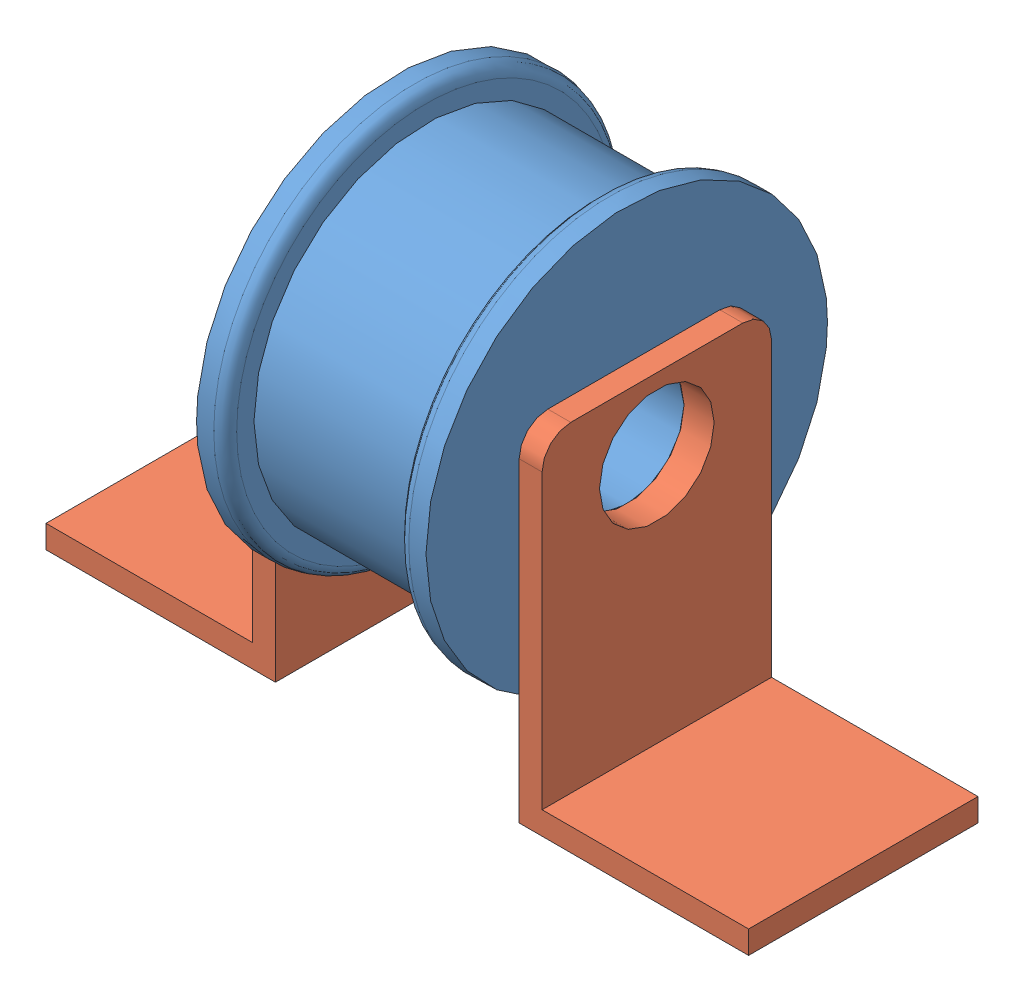
SolidWorks assembly Idler_Assem, configuration Default. Lengths in mm.
Overall size (77.79 46.04 31.75).
3 component instances, 2 part files, 6 mates.
Components (placement in the parent):
- Idler-1: Idler [Default] at origin size (25.4 31.75 31.75)
- Idler_Support-1: Idler_Support [Default] at (23.0188 -30.1625 -12.7) x (0 0 1) z (-1 0 0) size (25.4 38.1 26.19)
- Idler_Support-2: Idler_Support [Default] at (-3.9688 -30.1625 12.7) x (0 0 -1) z (1 0 0) size (25.4 38.1 26.19)
Mates (geometry in assembly coordinates):
- Concentric2: concentric anti-aligned: circle of Idler-1; circle of Idler_Support-1
- Coincident1: coincident anti-aligned: plane of Idler-1 through (22.225 0 0) normal (1 0 0); plane of Idler_Support-1 through (22.225 0 0) normal (-1 0 0)
- Coincident2: coincident anti-aligned: plane of Idler-1 through (-3.175 0 0) normal (-1 0 0); plane of Idler_Support-2 through (-3.175 0 0) normal (1 0 0)
- Concentric3: concentric anti-aligned: circle of Idler-1; circle of Idler_Support-2
- Parallel1: parallel anti-aligned: plane of Idler_Support-2 through (-3.9688 -30.1625 -12.7) normal (0 -1 0); plane of assembly through (0 0 0) normal (0 1 0)
- Parallel2: parallel anti-aligned: plane of Idler_Support-1 through (23.0188 -30.1625 12.7) normal (0 -1 0); plane of assembly through (0 0 0) normal (0 1 0)
